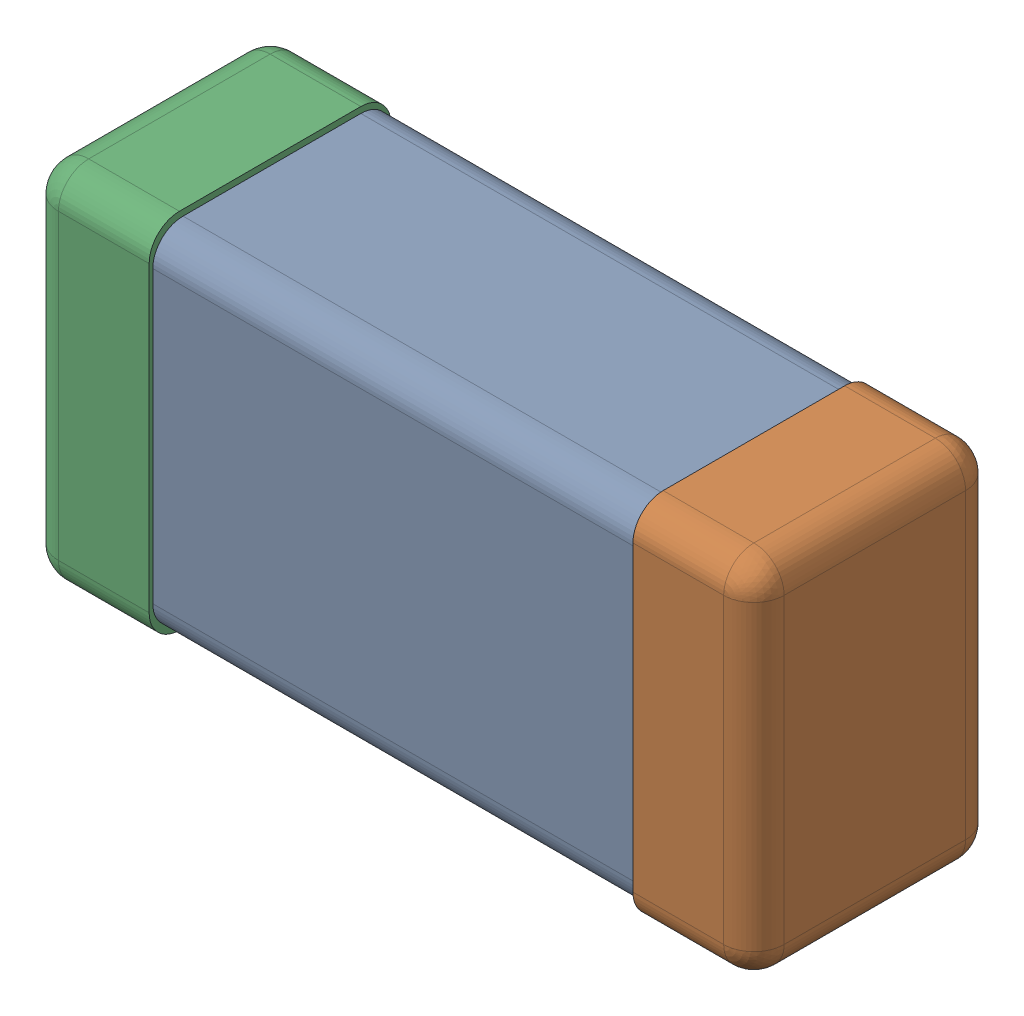
SolidWorks assembly C0201_020_33, configuration Standard. Lengths in mm.
Overall size (0.6 0.3 0.2).
3 component instances, 3 part files, 0 mates.
Components (placement in the parent):
- Part 3_2-1: Part 3_2 [Standard] at (0 0 -7.3015) size (0.5 0.29 0.2)
- Part 2_2-1: Part 2_2 [Standard] at (0 0 -7.3) size (0.1 0.3 0.2)
- Part 1_2-1: Part 1_2 [Standard] at (0 0 -7.3) size (0.1 0.3 0.2)
